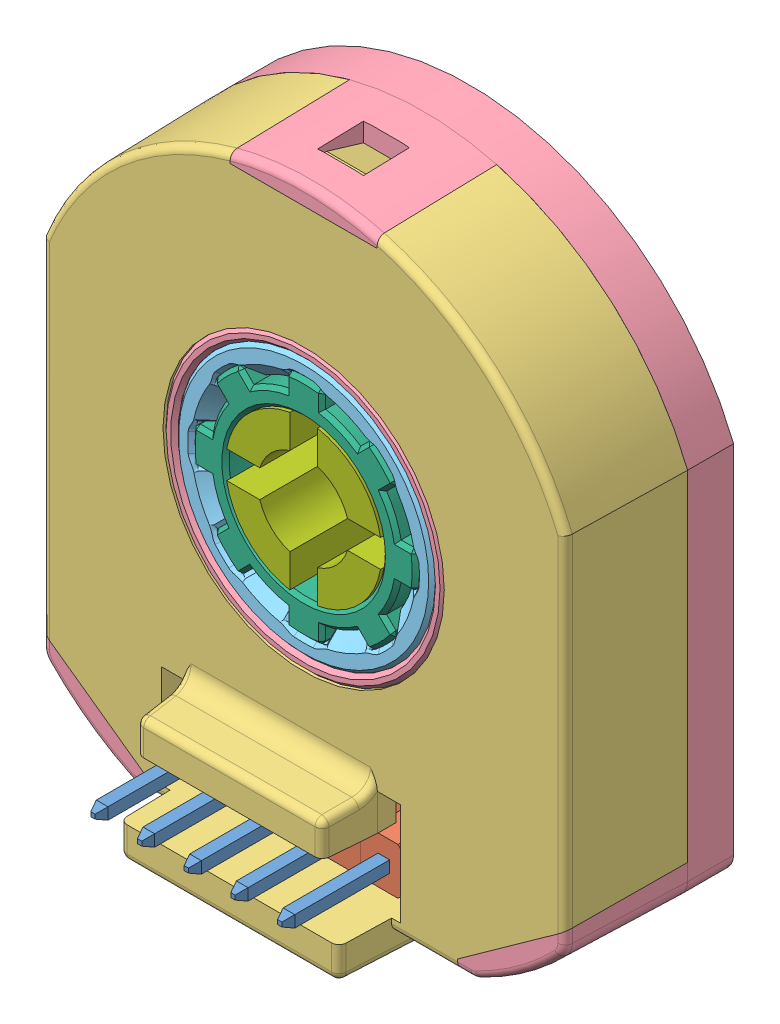
SolidWorks assembly ATM103 Encoder, configuration Default. Lengths in mm.
Overall size (28.77 34.38 14.22).
18 component instances, 7 part files, 0 mates.
Components (placement in the parent):
- ATM103 Encoder.step-1: ATM103 Encoder.step [Default] at origin size (28.77 34.38 14.22)
  - Array002.step-1: Array002.step [Default] at (-6.3 -15 3) size (10.79 0.64 11.2)
    - Body007.step-1: Body007.step [Default] at (0 0 -2.54) size (0.64 0.64 11.2)
    - Body007.step-2: Body007.step [Default] at (2.54 0 -2.54) size (0.64 0.64 11.2)
    - Body007.step-3: Body007.step [Default] at (5.08 0 -2.54) size (0.64 0.64 11.2)
    - Body007.step-4: Body007.step [Default] at (7.62 0 -2.54) size (0.64 0.64 11.2)
    - Body007.step-5: Body007.step [Default] at (10.16 0 -2.54) size (0.64 0.64 11.2)
  - Array003.step-1: Array003.step [Default] at (-6.3 -15 3) size (12.7 2.54 3)
    - Body008.step-1: Body008.step [Default] at origin size (2.54 2.54 3)
    - Body008.step-2: Body008.step [Default] at (2.54 0 0) size (2.54 2.54 3)
    - Body008.step-3: Body008.step [Default] at (5.08 0 0) size (2.54 2.54 3)
    - Body008.step-4: Body008.step [Default] at (7.62 0 0) size (2.54 2.54 3)
    - Body008.step-5: Body008.step [Default] at (10.16 0 0) size (2.54 2.54 3)
  - Body.step-1: Body.step [Default] at origin size (28.77 33.84 9.3)
  - Body001.step-1: Body001.step [Default] at origin size (28.77 34.38 9.03)
  - Chamfer002.step-1: Chamfer002.step [Default] at origin size (14 14 9.13)
  - Chamfer004.step-1: Chamfer004.step [Default] at (0 0 0.5) size (12.2 12.2 9)
  - Body006.step-1: Body006.step [Default] at (0 0 -2.5) size (9 9 9)
